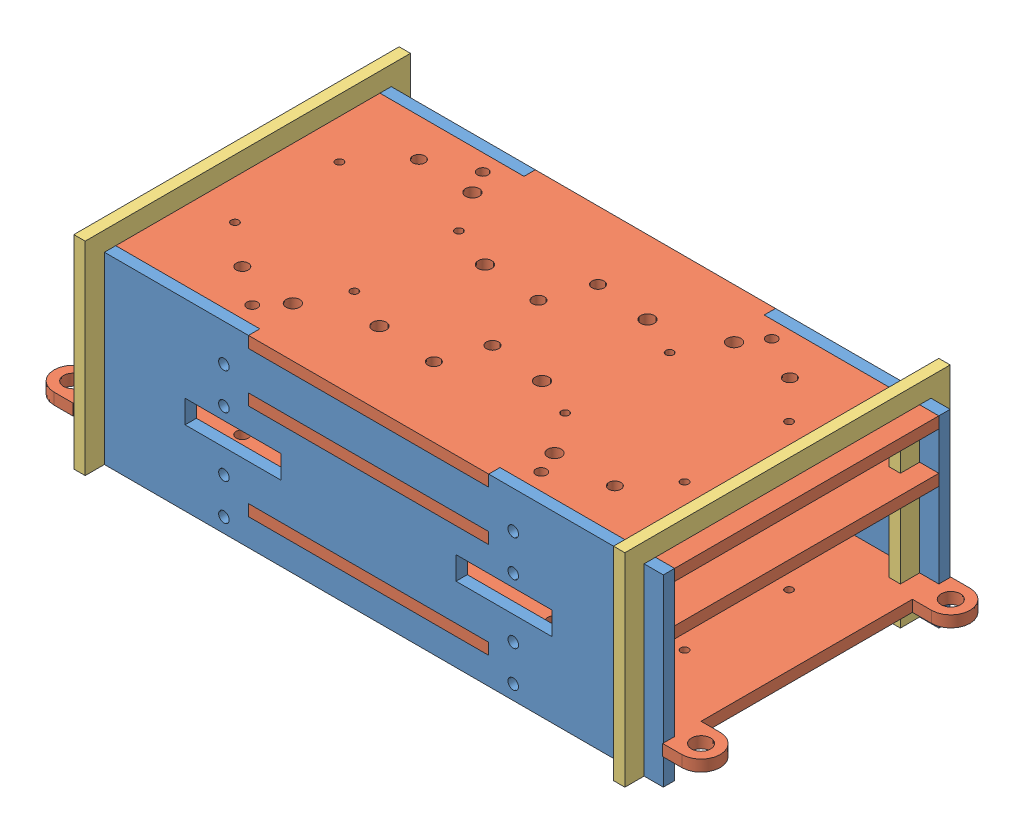
SolidWorks assembly Basic Assembly of PcDuino Enclosure, configuration Default. Lengths in mm.
Overall size (176.17 53.7 86).
7 component instances, 3 part files, 17 mates.
Components (placement in the parent):
- Wall-1: Wall [Default] at (-131.8828 -20.6838 34.7987) size (155.85 48.62 3)
- Wall-2: Wall [Default] at (-131.8828 -20.6838 -38.0485) size (155.85 48.62 3)
- Floors-1: Floors [Default] at (-131.8828 -14.3338 34.7987) x (1 0 0) z (0 1 0) size (176.17 76.2 3)
- Floors-2: Floors [Slider peice] at (-131.8828 24.1726 34.7987) x (1 0 0) z (0 1 0) size (155.85 75.84 3)
- Floors-3: Floors [Slider peice] at (-131.8828 11.0154 34.7987) x (1 0 0) z (0 1 0) size (155.85 75.84 3)
- gate-1: gate [Default] at (10.8144 -20.6838 -38.0485) x (0 0 1) z (-1 0 0) size (86 53.7 3)
- gate-2: gate [Default] at (-131.8828 -20.6838 -38.0485) x (0 0 1) z (-1 0 0) size (86 53.7 3)
Mates (geometry in assembly coordinates):
- Coincident1: coincident aligned: plane of Wall-1 through (-131.8828 24.1726 37.7959) normal (0 1 0); plane of Wall-2 through (-131.8828 24.1726 -35.0513) normal (0 1 0)
- Coincident2: coincident aligned: plane of Wall-1 through (-134.88 -20.6838 37.7959) normal (1 0 0); plane of Wall-2 through (-134.88 -20.6838 -35.0513) normal (1 0 0)
- Distance1: distance = 69.85 mm anti-aligned: plane of Wall-2 through (-131.8828 -20.6838 -35.0513) normal (0 0 1); plane of Wall-1 through (-131.8828 -20.6838 34.7987) normal (0 0 -1)
- InPlace1: in place: plane of Wall-1 through (-131.8828 -14.3338 37.7959) normal (0 1 0); plane of ? through (0 -14.3338 0) normal (0 1 0); moOrthogonalPlaneRef_w of Wall-1 through (-131.8828 -14.3338 37.7959) normal (0 1 0); plane of ? through (0 -14.3338 0) normal (0 0 -1); plane of Wall-1 through (-131.8828 -14.3338 37.7959) normal (0 1 0); line of ? through (-55 0 -14.3338) axis (0 1 0); plane of Wall-1 through (-131.8828 -14.3338 37.7959) normal (0 1 0); unknown of Floors-1
- Coincident4: coincident aligned: plane of Wall-1; plane of Floors-1
- Coincident5: coincident aligned: moOrthogonalPlaneRef_w of Wall-1 through (-131.8828 -14.3338 34.7987) normal (0 0 -1); plane of Floors-1 through (-131.8828 -14.3338 34.7987) normal (0 0 -1)
- Coincident6: coincident anti-aligned: moOrthogonalPlaneRef_w of Wall-1 through (-131.8828 -14.3338 34.7987) normal (-1 0 0); plane of Floors-1
- Coincident7: coincident anti-aligned: plane of Wall-2 through (-131.8828 14.0126 -35.0513) normal (0 -1 0); plane of Floors-3 through (-131.8828 14.0126 34.7987) normal (0 1 0)
- Coincident9: coincident aligned: plane of Wall-1 through (-131.8828 -20.6838 37.7959) normal (0 0 1); plane of Floors-3 through (-93.7828 14.0126 37.7959) normal (0 0 1)
- Coincident10: coincident aligned: plane of Wall-1 through (-131.8828 -20.6838 37.7959) normal (0 0 1); plane of Floors-2 through (-93.7828 27.1698 37.7959) normal (0 0 1)
- Coincident11: coincident anti-aligned: plane of Wall-1 through (-131.8828 24.1726 37.7959) normal (0 1 0); plane of Floors-2 through (-131.8828 24.1726 34.7987) normal (0 -1 0)
- Coincident12: coincident anti-aligned: plane of Wall-2 through (10.8144 -20.6838 -35.0513) normal (-1 0 0); plane of gate-1 through (10.8144 -20.6838 -38.0485) normal (1 0 0)
- Coincident13: coincident anti-aligned: plane of Wall-2 through (-131.8828 -20.6838 -35.0513) normal (0 0 1); plane of gate-1 through (7.8172 3.243 -35.0513) normal (0 0 -1)
- Coincident14: coincident anti-aligned: plane of Wall-2 through (-131.8828 3.243 -35.0513) normal (0 1 0); plane of gate-1 through (7.8172 3.243 -38.0485) normal (0 -1 0)
- Coincident15: coincident anti-aligned: plane of Wall-1 through (-131.8828 -20.6838 37.7959) normal (-1 0 0); plane of gate-2 through (-131.8828 -20.6838 -38.0485) normal (1 0 0)
- Coincident16: coincident anti-aligned: plane of Wall-1 through (-131.8828 -20.6838 37.7959) normal (0 0 1); plane of gate-2 through (-134.88 -21.4458 37.7959) normal (0 0 -1)
- Coincident17: coincident anti-aligned: plane of Wall-2 through (-131.8828 3.243 -35.0513) normal (0 1 0); plane of gate-2 through (-134.88 3.243 -38.0485) normal (0 -1 0)
